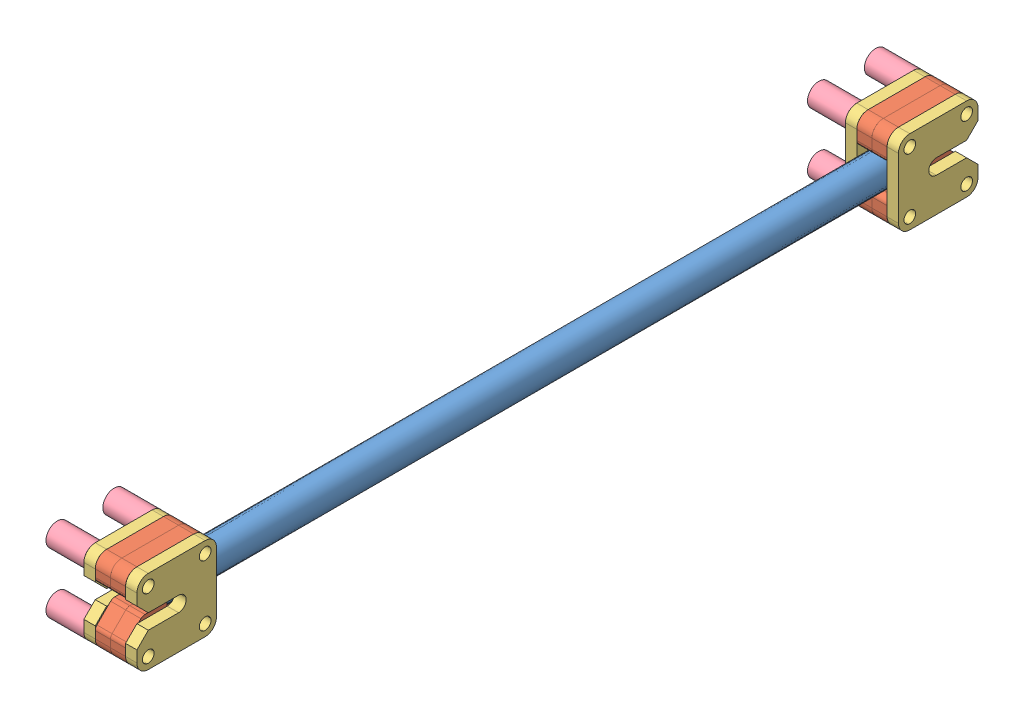
SolidWorks assembly 俯仰轨道, configuration 默认. Lengths in mm.
Overall size (24 22 222).
21 component instances, 4 part files, 48 mates.
Components (placement in the parent):
- 直径8光轴_俯仰角-1: 直径8光轴_俯仰角 [默认] at origin size (8 8 203)
- 轨道光轴固定（直径8）-1: 轨道光轴固定（直径8） [默认] at (2 11 -100.5) x (0 0 1) z (-1 0 0) size (21 10.05 4)
- 轨道光轴固定（直径8）-2: 轨道光轴固定（直径8） [默认] at (-2 11 -100.5) x (0 0 1) z (-1 0 0) size (21 10.05 4)
- 轨道光轴固定（直径8）-3: 轨道光轴固定（直径8） [默认] at (2 -11 -100.5) x (0 0 1) z (1 0 0) size (21 10.05 4)
- 轨道光轴固定（直径8）-4: 轨道光轴固定（直径8） [默认] at (-2 -11 -100.5) x (0 0 1) z (1 0 0) size (21 10.05 4)
- 轨道光轴固定（直径8）-5: 轨道光轴固定（直径8） [默认] at (-2 11 100.5) x (0 0 -1) z (1 0 0) size (21 10.05 4)
- 轨道光轴固定（直径8）-6: 轨道光轴固定（直径8） [默认] at (2 11 100.5) x (0 0 -1) z (1 0 0) size (21 10.05 4)
- 轨道光轴固定（直径8）-7: 轨道光轴固定（直径8） [默认] at (2 -11 100.5) x (0 0 -1) z (-1 0 0) size (21 10.05 4)
- 轨道光轴固定（直径8）-8: 轨道光轴固定（直径8） [默认] at (-2 -11 100.5) x (0 0 -1) z (-1 0 0) size (21 10.05 4)
- 轨道光轴固定侧板-1: 轨道光轴固定侧板 [默认] at (5.5 0 1) size (3 22 21)
- 轨道光轴固定侧板-3: 轨道光轴固定侧板 [默认] at (-5.5 0 -1) x (-1 0 0) z (0 0 -1) size (3 22 21)
- 轨道光轴固定侧板-4: 轨道光轴固定侧板 [默认] at (5.5 0 -1) x (-1 0 0) z (0 0 -1) size (3 22 21)
- 轨道光轴固定侧板-5: 轨道光轴固定侧板 [默认] at (-5.5 0 1) size (3 22 21)
- M3×Φ6×10-1: M3×Φ6×10 [默认] at (-12 -8 -93) x (0 0 -1) z (1 0 0) size (6 6 10)
- M3×Φ6×10-2: M3×Φ6×10 [默认] at (-12 -8 -108) x (0 0 -1) z (1 0 0) size (6 6 10)
- M3×Φ6×10-3: M3×Φ6×10 [默认] at (-12 8 -93) x (0 0 -1) z (1 0 0) size (6 6 10)
- M3×Φ6×10-4: M3×Φ6×10 [默认] at (-12 8 -108) x (0 0 -1) z (1 0 0) size (6 6 10)
- M3×Φ6×10-5: M3×Φ6×10 [默认] at (-12 -8 93) x (0 0 1) z (-1 0 0) size (6 6 10)
- M3×Φ6×10-6: M3×Φ6×10 [默认] at (-12 -8 108) x (0 0 1) z (-1 0 0) size (6 6 10)
- M3×Φ6×10-7: M3×Φ6×10 [默认] at (-12 8 93) x (0 0 1) z (-1 0 0) size (6 6 10)
- M3×Φ6×10-8: M3×Φ6×10 [默认] at (-12 8 108) x (0 0 1) z (-1 0 0) size (6 6 10)
Mates (geometry in assembly coordinates):
- 重合1: coincident aligned: plane of 直径8光轴_俯仰角-1 through (0 0 0) normal (0 0 1)
- 重合2: coincident aligned: plane of 直径8光轴_俯仰角-1 through (0 0 0) normal (0 1 0)
- 重合3: coincident aligned: plane of 直径8光轴_俯仰角-1 through (0 0 0) normal (1 0 0)
- 同心3: concentric aligned: cylinder of 轨道光轴固定（直径8）-1 through (0 8 -108) axis (1 0 0) radius 1.55; cylinder of 轨道光轴固定（直径8）-2 through (-4 8 -108) axis (1 0 0) radius 1.55
- 同心5: concentric aligned: cylinder of 轨道光轴固定（直径8）-1 through (0 8 -93) axis (1 0 0) radius 1.55; cylinder of 轨道光轴固定（直径8）-2 through (-4 8 -93) axis (1 0 0) radius 1.55
- 重合6: coincident anti-aligned: plane of 轨道光轴固定（直径8）-1 through (0 11 -100.5) normal (-1 0 0); plane of 轨道光轴固定（直径8）-2 through (0 11 -100.5) normal (1 0 0)
- 同心8: concentric aligned: cylinder of 轨道光轴固定（直径8）-3 through (4 -8 -108) axis (-1 0 0) radius 1.55; cylinder of 轨道光轴固定（直径8）-4 through (0 -8 -108) axis (-1 0 0) radius 1.55
- 同心9: concentric aligned: cylinder of 轨道光轴固定（直径8）-3 through (4 -8 -93) axis (-1 0 0) radius 1.55; cylinder of 轨道光轴固定（直径8）-4 through (0 -8 -93) axis (-1 0 0) radius 1.55
- 重合8: coincident anti-aligned: plane of 轨道光轴固定（直径8）-3 through (0 -11 -100.5) normal (-1 0 0); plane of 轨道光轴固定（直径8）-4 through (0 -11 -100.5) normal (1 0 0)
- 重合9: coincident anti-aligned: plane of 直径8光轴_俯仰角-1 through (0 0 -101.5) normal (0 0 -1); plane of 轨道光轴固定（直径8）-1 through (0 3.95 -101.5) normal (0 0 1)
- 重合12: coincident anti-aligned: plane of 轨道光轴固定（直径8）-5 through (0 11 100.5) normal (1 0 0); plane of 轨道光轴固定（直径8）-6 through (0 11 100.5) normal (-1 0 0)
- 同心10: concentric aligned: cylinder of 轨道光轴固定（直径8）-5 through (0 8 93) axis (-1 0 0) radius 1.55; cylinder of 轨道光轴固定（直径8）-6 through (4 8 93) axis (-1 0 0) radius 1.55
- 同心11: concentric aligned: cylinder of 轨道光轴固定（直径8）-5 through (0 8 108) axis (-1 0 0) radius 1.55; cylinder of 轨道光轴固定（直径8）-6 through (4 8 108) axis (-1 0 0) radius 1.55
- 重合14: coincident anti-aligned: plane of 直径8光轴_俯仰角-1 through (0 0 101.5) normal (0 0 1); plane of 轨道光轴固定（直径8）-5 through (0 3.95 101.5) normal (0 0 -1)
- 同心14: concentric aligned: cylinder of 轨道光轴固定（直径8）-7 through (0 -8 108) axis (1 0 0) radius 1.55; cylinder of 轨道光轴固定（直径8）-8 through (-4 -8 108) axis (1 0 0) radius 1.55
- 同心15: concentric aligned: cylinder of 轨道光轴固定（直径8）-7 through (0 -8 93) axis (1 0 0) radius 1.55; cylinder of 轨道光轴固定（直径8）-8 through (-4 -8 93) axis (1 0 0) radius 1.55
- 重合15: coincident anti-aligned: plane of 轨道光轴固定（直径8）-7 through (0 -11 100.5) normal (-1 0 0); plane of 轨道光轴固定（直径8）-8 through (0 -11 100.5) normal (1 0 0)
- 相切4: tangent aligned: cylinder of 直径8光轴_俯仰角-1 through (0 0 101.5) axis (0 0 -1) radius 4; plane of 轨道光轴固定（直径8）-6 through (4 11 100.5) normal (1 0 0)
- 同心16: concentric aligned: cylinder of 轨道光轴固定（直径8）-6 through (4 8 108) axis (-1 0 0) radius 1.55; cylinder of 轨道光轴固定侧板-1 through (7 8 108) axis (-1 0 0) radius 1.55
- 同心17: concentric aligned: cylinder of 轨道光轴固定（直径8）-6 through (4 8 93) axis (-1 0 0) radius 1.55; cylinder of 轨道光轴固定侧板-1 through (7 8 93) axis (-1 0 0) radius 1.55
- 同心18: concentric anti-aligned: cylinder of 轨道光轴固定（直径8）-7 through (0 -8 108) axis (1 0 0) radius 1.55; cylinder of 轨道光轴固定侧板-1 through (7 -8 108) axis (-1 0 0) radius 1.55
- 同心19: concentric anti-aligned: cylinder of 轨道光轴固定（直径8）-7 through (0 -8 93) axis (1 0 0) radius 1.55; cylinder of 轨道光轴固定侧板-1 through (7 -8 93) axis (-1 0 0) radius 1.55
- 重合16: coincident anti-aligned: plane of 轨道光轴固定（直径8）-6 through (4 11 100.5) normal (1 0 0); plane of 轨道光轴固定侧板-1 through (4 0 100) normal (-1 0 0)
- 重合17: coincident anti-aligned: plane of 轨道光轴固定（直径8）-7 through (4 -11 100.5) normal (1 0 0); plane of 轨道光轴固定侧板-1 through (4 0 100) normal (-1 0 0)
- 平行1: parallel aligned: plane of 轨道光轴固定侧板-1 through (7 0 100) normal (1 0 0)
- 对称1: symmetric aligned: plane of 轨道光轴固定（直径8）-5 through (0 0.95 101.5) normal (0 -1 0); plane of 轨道光轴固定（直径8）-8 through (-4 -0.95 101.5) normal (0 1 0)
- 同心24: concentric anti-aligned: circle of 轨道光轴固定（直径8）-2; cylinder of 轨道光轴固定侧板-3 through (-7 8 -108) axis (1 0 0) radius 1.55
- 同心25: concentric aligned: cylinder of 轨道光轴固定（直径8）-2 through (-4 8 -93) axis (1 0 0) radius 1.55; cylinder of 轨道光轴固定侧板-3 through (-7 8 -93) axis (1 0 0) radius 1.55
- 同心26: concentric anti-aligned: cylinder of 轨道光轴固定（直径8）-4 through (0 -8 -108) axis (-1 0 0) radius 1.55; cylinder of 轨道光轴固定侧板-3 through (-7 -8 -108) axis (1 0 0) radius 1.55
- 重合20: coincident anti-aligned: plane of 轨道光轴固定（直径8）-2 through (-4 11 -100.5) normal (-1 0 0); plane of 轨道光轴固定侧板-3 through (-4 0 -100) normal (1 0 0)
- 重合21: coincident aligned: plane of 轨道光轴固定（直径8）-5 through (0 11 111) normal (0 1 0); plane of 轨道光轴固定侧板-3 through (-7 11 -90) normal (0 1 0)
- 重合22: coincident anti-aligned: plane of 轨道光轴固定（直径8）-3 through (4 -11 -100.5) normal (1 0 0); plane of 轨道光轴固定侧板-4 through (4 0 -100) normal (-1 0 0)
- 同心27: concentric aligned: cylinder of 轨道光轴固定（直径8）-1 through (0 8 -108) axis (1 0 0) radius 1.55; cylinder of 轨道光轴固定侧板-4 through (4 8 -108) axis (1 0 0) radius 1.55
- 同心28: concentric aligned: cylinder of 轨道光轴固定（直径8）-1 through (0 8 -93) axis (1 0 0) radius 1.55; cylinder of 轨道光轴固定侧板-4 through (4 8 -93) axis (1 0 0) radius 1.55
- 同心29: concentric anti-aligned: cylinder of 轨道光轴固定（直径8）-3 through (4 -8 -93) axis (-1 0 0) radius 1.55; cylinder of 轨道光轴固定侧板-4 through (4 -8 -93) axis (1 0 0) radius 1.55
- 重合23: coincident anti-aligned: plane of 轨道光轴固定（直径8）-4 through (-4 -11 -100.5) normal (-1 0 0); plane of 轨道光轴固定侧板-3 through (-4 0 -100) normal (1 0 0)
- 重合24: coincident aligned: plane of 轨道光轴固定侧板-1 through (7 0 100) normal (1 0 0); plane of 轨道光轴固定侧板-4 through (7 0 -100) normal (1 0 0)
- 同心30: concentric aligned: cylinder of 轨道光轴固定（直径8）-5 through (0 8 93) axis (-1 0 0) radius 1.55; cylinder of 轨道光轴固定侧板-5 through (-4 8 93) axis (-1 0 0) radius 1.55
- 同心31: concentric aligned: cylinder of 轨道光轴固定（直径8）-5 through (0 8 108) axis (-1 0 0) radius 1.55; cylinder of 轨道光轴固定侧板-5 through (-4 8 108) axis (-1 0 0) radius 1.55
- 重合25: coincident anti-aligned: plane of 轨道光轴固定（直径8）-5 through (-4 11 100.5) normal (-1 0 0); plane of 轨道光轴固定侧板-5 through (-4 0 100) normal (1 0 0)
- 同心38: concentric anti-aligned: cylinder of 轨道光轴固定侧板-3 through (-7 8 -108) axis (1 0 0) radius 1.55; cylinder of M3×Φ6×10-4 through (-7 8 -108) axis (-1 0 0) radius 1.5
- 同心39: concentric anti-aligned: cylinder of 轨道光轴固定侧板-3 through (-7 8 -93) axis (1 0 0) radius 1.55; cylinder of M3×Φ6×10-3 through (-7 8 -93) axis (-1 0 0) radius 1.5
- 同心40: concentric anti-aligned: cylinder of 轨道光轴固定侧板-3 through (-7 -8 -108) axis (1 0 0) radius 1.55; cylinder of M3×Φ6×10-2 through (-7 -8 -108) axis (-1 0 0) radius 1.5
- 同心41: concentric anti-aligned: cylinder of 轨道光轴固定侧板-3 through (-7 -8 -93) axis (1 0 0) radius 1.55; cylinder of M3×Φ6×10-1 through (-7 -8 -93) axis (-1 0 0) radius 1.5
- 重合28: coincident anti-aligned: plane of 轨道光轴固定侧板-3 through (-7 0 -100) normal (-1 0 0); plane of M3×Φ6×10-4 through (-7 8 -108) normal (1 0 0)
- 重合29: coincident anti-aligned: plane of 轨道光轴固定侧板-3 through (-7 0 -100) normal (-1 0 0); plane of M3×Φ6×10-3 through (-7 8 -93) normal (1 0 0)
- 重合30: coincident anti-aligned: plane of 轨道光轴固定侧板-3 through (-7 0 -100) normal (-1 0 0); plane of M3×Φ6×10-1 through (-7 -8 -93) normal (1 0 0)
- 重合31: coincident anti-aligned: plane of 轨道光轴固定侧板-3 through (-7 0 -100) normal (-1 0 0); plane of M3×Φ6×10-2 through (-7 -8 -108) normal (1 0 0)
